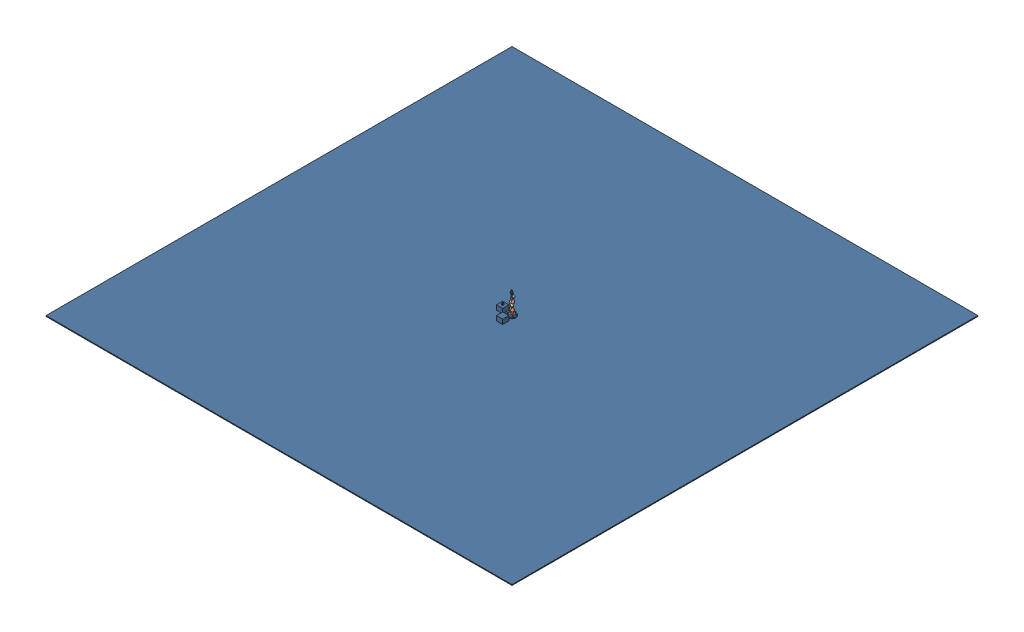
SolidWorks assembly kuka_robot, configuration Default. Lengths in mm.
Overall size (30000 1601.75 30000).
12 component instances, 10 part files, 15 mates.
Components (placement in the parent):
- Base-1: Base [Default] at (171.4541 169.4345 421.3751) size (508 127 508)
- Link_1-1: Link_1 [Default] at (171.4541 296.4345 421.3751) size (211.49 376.96 175.09)
- Link_3-1: Link_3 [Default] at (171.4541 704.2442 423.4336) x (-0.9969 -0.000789 0.078673) z (-0.078677 0.009995 -0.99685) size (209.6 354.94 137.32)
- Link_4-1: Link_4 [Default] at (171.0943 1120.7969 423.0502) x (-0.078656 -0.012763 -0.99682) z (-0.9969 -0.000789 0.078673) size (136.88 276.25 234.28)
- Link_5-1: Link_5 [Default] at (171.0943 1120.7969 423.0502) x (0.999998 0.001788 -0.000228) z (0.000205 0.012662 0.99992) size (253.21 311.38 136.88)
- Link_6-1: Link_6 [Default] at (233.4399 1290.825 420.8843) x (0.000325 -0.054324 0.998523) z (0.001773 -0.998522 -0.054325) size (104.55 123.69 187.76)
- Link_2-2: Link_2 [Default] at (171.4541 704.2442 423.4336) x (0 -0.010026 0.99995) z (1 0 0) size (172.1 302.29 205.13)
- Gripper-2: Gripper [Default] at (170.6789 1353.2704 424.3021) x (-0.518119 -0.047381 0.853995) z (-0.855307 0.026633 -0.517437) size (103.88 76.7 103.88)
- Gripper_Hands-1: Gripper_Hands [Default] at (150.9353 1394.5211 390.6944) x (-0.47969 -0.04 -0.876526) z (0.876357 0.027717 -0.480863) size (78.87 220.37 34.4)
- Gripper_Hands-2: Gripper_Hands [Default] at (149.4433 1390.6757 461.3263) x (-0.517995 -0.066037 0.852831) z (-0.855307 0.026633 -0.517437) size (78.87 220.37 34.4)
- Gripper_Hands-3: Gripper_Hands [Default] at (211.4488 1392.6367 427.3064) x (0.993264 -0.114939 0.014687) z (-0.021051 -0.05435 0.9983) size (78.87 220.37 34.4)
- test_world-1: test_world [Default] at (171.4541 169.4345 421.3751) x (-1 0 0) z (0 0 1) size (30000 450 30000)
Mates (geometry in assembly coordinates):
- ProfileCenter1: profile center anti-aligned: plane of Base-1 through (171.4541 220.2345 421.3751) normal (0 1 0); plane of Link_1-1 through (171.4541 220.2345 421.3751) normal (0 -1 0)
- ProfileCenter4: profile center anti-aligned: plane of Link_3-1 through (120.8116 919.7833 429.5917) normal (0.9969 0.000789 -0.078673); plane of Link_4-1 through (120.8116 919.7833 429.5917) normal (-0.9969 -0.000789 0.078673)
- ProfileCenter5: profile center anti-aligned: circle of Link_5-1; plane of Link_4-1 through (171.1852 1070.0011 423.6935) normal (-0.00179 0.999918 -0.012662)
- ProfileCenter6: profile center anti-aligned: plane of Link_5-1 through (182.64 1290.7342 420.8959) normal (-0.999998 -0.001788 0.000228); plane of Link_6-1 through (182.64 1290.7342 420.8959) normal (0.999998 0.001788 -0.000228)
- ProfileCenter7: profile center anti-aligned: plane of Link_2-2 through (222.2541 498.9445 421.3751) normal (1 0 0); plane of Link_1-1 through (222.2541 498.9445 421.3751) normal (-1 0 0)
- ProfileCenter8: profile center anti-aligned: plane of Link_3-1 through (171.4541 653.4468 422.9242) normal (0 -0.99995 -0.010026); plane of Link_2-2 through (171.4541 653.4468 422.9242) normal (0 0.99995 0.010026)
- ProfileCenter10: profile center anti-aligned: plane of Link_6-1 through (170.724 1327.908 422.9222) normal (-0.001773 0.998522 0.054325); plane of Gripper-2 through (170.724 1327.908 422.9222) normal (0.001773 -0.998522 -0.054325)
- ProfileCenter11: profile center aligned: plane of Gripper_Hands-3 through (211.8108 1393.5715 410.1357) normal (0.021051 0.05435 -0.9983); plane of Gripper-2 through (211.8108 1393.5715 410.1357) normal (-0.021051 -0.05435 0.9983)
- ProfileCenter12: profile center aligned: plane of Gripper_Hands-1 through (135.8619 1394.0444 398.9653) normal (-0.876357 -0.027717 0.480863); plane of Gripper-2 through (135.8619 1394.0444 398.9653) normal (0.876357 0.027717 -0.480863)
- ProfileCenter13: profile center aligned: plane of Gripper_Hands-2 through (164.1546 1390.2177 470.2262) normal (0.855307 -0.026633 0.517437); plane of Gripper-2 through (164.1546 1390.2177 470.2262) normal (-0.855307 0.026633 -0.517437)
- Concentric1: concentric aligned: circle of Gripper-2; circle of Gripper_Hands-2
- Concentric2: concentric aligned: circle of Gripper-2; circle of Gripper_Hands-1
- Concentric3: concentric aligned: circle of Gripper-2; circle of Gripper_Hands-3
- Coincident2: coincident aligned: circle of Base-1; circle of test_world-1
- Concentric4: concentric aligned: circle of Base-1; circle of test_world-1
